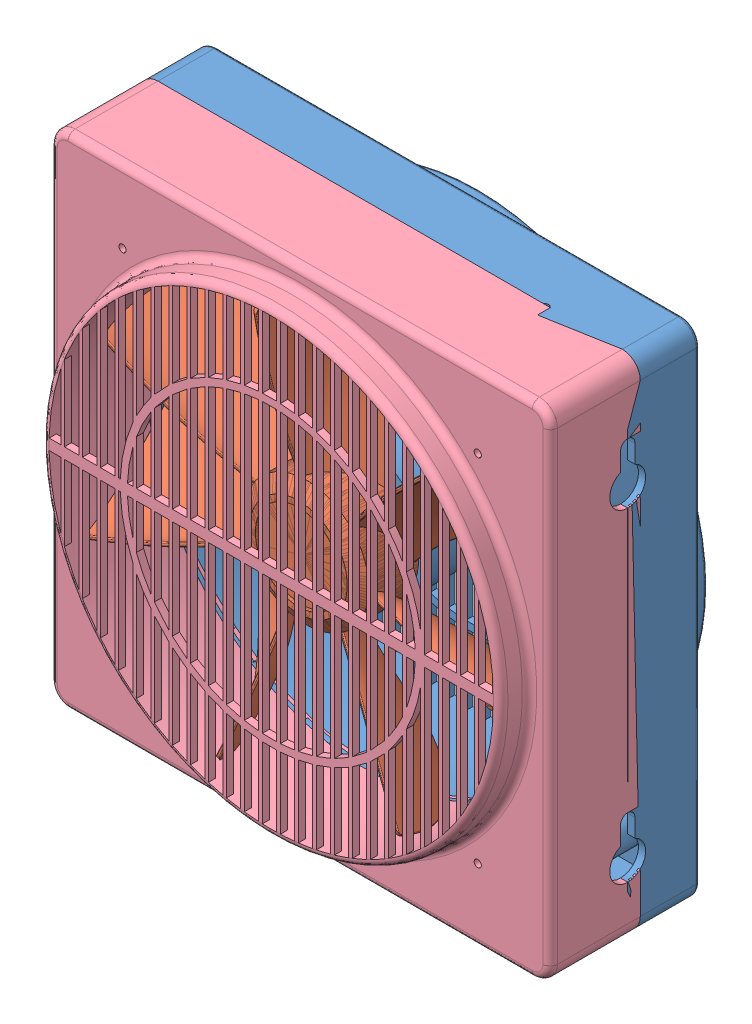
SolidWorks assembly Assembly Mini DC Fan, configuration Default. Lengths in mm.
Overall size (139 139 57.5).
4 component instances, 4 part files, 8 mates.
Components (placement in the parent):
- box_back-1: box_back [Default] at (49.426 74.2264 98.3448) size (139 139 33)
- impeller-1: impeller [Default] at (49.426 74.2264 140.3448) x (-0.036359 0.999339 0) z (0 0 1) size (128.05 126.85 47.77)
- pemegang-1: pemegang [Default] at (49.426 74.2264 90.3448) x (0.5 0.866025 0) z (0 0 1) size (36.14 36.7 6.6)
- box_front-1: box_front [Default] at (49.426 74.2264 139.8448) x (-1 0 0) z (0 0 -1) size (139 139 38)
Mates (geometry in assembly coordinates):
- Concentric1: concentric anti-aligned: cylinder of box_back-1 through (49.426 74.2264 98.3448) axis (0 0 -1) radius 18; circle of pemegang-1
- Coincident2: coincident aligned: plane of box_back-1 through (59.6173 83.5745 92.3448) normal (0.5 -0.866025 0); plane of pemegang-1 through (65.6434 87.0536 91.4448) normal (0.5 -0.866025 0)
- Coincident3: coincident aligned: plane of box_back-1 through (49.426 74.2264 90.3448) normal (0 0 -1); plane of pemegang-1 through (49.426 74.2264 90.3448) normal (0 0 -1)
- Coincident5: coincident anti-aligned: plane of box_back-1 through (-15.074 9.7264 118.3448) normal (0 0 1); plane of box_front-1 through (113.426 10.2264 118.3448) normal (0 0 -1)
- Coincident6: coincident aligned: plane of box_back-1 through (118.926 138.7264 123.3448) normal (1 0 0); plane of box_front-1 through (118.926 138.7264 114.8448) normal (1 0 0)
- Coincident7: coincident aligned: plane of box_back-1 through (-15.074 4.7264 123.3448) normal (0 -1 0); plane of box_front-1 through (113.926 4.7264 114.8448) normal (0 -1 0)
- Distance1: distance = 2 mm anti-aligned: plane of box_back-1 through (49.426 74.2264 122.3448) normal (0 0 1); plane of impeller-1 through (49.426 74.2264 124.3448) normal (0 0 -1)
- Concentric2: concentric anti-aligned: cylinder of box_back-1 through (49.426 74.2264 120.3448) axis (0 0 1) radius 5; cylinder of impeller-1 through (49.426 74.2264 137.3448) axis (0 0 -1) radius 1
